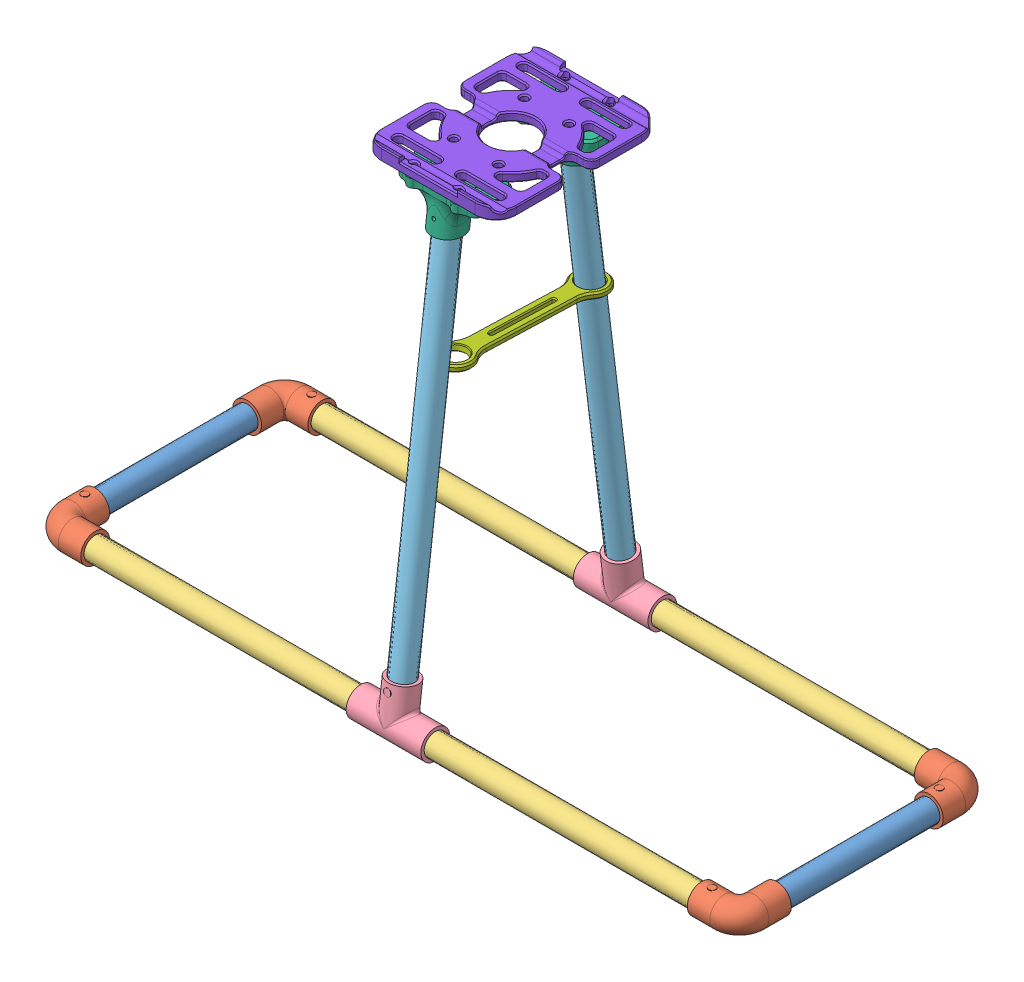
SolidWorks assembly Work Station 010, configuration Predeterminado. Lengths in mm.
Overall size (683 457.41 249.42).
18 component instances, 8 part files, 49 mates.
Components (placement in the parent):
- PVC 90mm-1: PVC 90mm [Predeterminado] at (-25.3323 -2.3435 90) size (21.4 21.4 190)
- PVC 90mm-2: PVC 90mm [Predeterminado] at (629.9177 -2.3435 90) x (-0.183139 -0.983087 0) z (0 0 1) size (21.4 21.4 190)
- PVC 90 Degree Connector-1: PVC 90 Degree Connector [Predeterminado] at (-25.3323 -2.3435 -18.625) x (0 0 -1) z (1 0 0) size (50 27.88 50)
- PVC 90 Degree Connector-2: PVC 90 Degree Connector [Predeterminado] at (629.9177 -2.3435 -18.625) size (50 27.88 50)
- PVC 90 Degree Connector-3: PVC 90 Degree Connector [Predeterminado] at (-25.3323 -2.3435 199.625) x (-1 0 0) z (0 0 -1) size (50 27.88 50)
- PVC 90 Degree Connector-4: PVC 90 Degree Connector [Predeterminado] at (629.9177 -2.3435 199.625) x (0 0 1) z (-1 0 0) size (50 27.88 50)
- PVC 300mm-1: PVC 300mm [Predeterminado] at (138.2927 -2.3435 -18.625) x (0 0.747452 -0.664316) z (1 0 0) size (21.4 21.4 300)
- PVC 300mm-2: PVC 300mm [Predeterminado] at (139.2927 -2.3435 199.625) x (0 0.600314 -0.799764) z (1 0 0) size (21.4 21.4 300)
- PVC 300mm-3: PVC 300mm [Predeterminado] at (465.2927 -2.3435 -18.625) x (0 -0.428598 -0.903495) z (1 0 0) size (21.4 21.4 300)
- PVC 300mm-4: PVC 300mm [Predeterminado] at (465.2927 -2.3435 199.625) x (0 0.714815 0.699313) z (1 0 0) size (21.4 21.4 300)
- PVC T Connector-1: PVC T Connector [Predeterminado] at (301.7927 -2.3435 -18.625) x (0 0.121869 -0.992546) z (1 0 0) size (27.88 50.37 71.8)
- PVC 415mm-1: PVC 415mm [Predeterminado] at (301.7927 217.5055 172.6309) x (-0.698282 -0.087237 -0.710487) z (0 0.992546 -0.121869) size (21.4 21.4 415)
- PVC 415mm-2: PVC 415mm [Predeterminado] at (301.7927 217.7536 8.3995) x (-0.874766 -0.059051 0.480934) z (0 -0.992546 -0.121869) size (21.4 21.4 415)
- PVC T Connector-3: PVC T Connector [Predeterminado] at (301.7927 -2.3435 199.625) x (0 0.121869 0.992546) z (-1 0 0) size (27.88 50.37 71.8)
- Rest Plate Connector 100-1: Rest Plate Connector 100 [Predeterminado] at (301.7927 427.1913 36.6289) size (80 42.81 49)
- Rest Plate Connector 100-2: Rest Plate Connector 100 [Predeterminado] at (301.7927 427.1913 144.3711) x (-1 0 0) z (0 0 -1) size (80 42.81 49)
- Spacer 010-1: Spacer 010 [Predeterminado] at (301.8957 270.2027 80.3275) x (0.001566 0.0349 0.99939) z (-0.999999 -0.000193 0.001573) size (162.46 11.66 32)
- Rest Plate Fixture 010-1: Rest Plate Fixture 010 [Default] at (301.7927 435.6913 90.5) x (0 0 1) z (1 0 0) size (160 12.41 130)
Mates (geometry in assembly coordinates):
- Concéntrica1: concentric aligned: cylinder of PVC 90mm-1 through (-25.3323 -2.3435 185) axis (0 0 -1) radius 10.7; cylinder of PVC 90 Degree Connector-1 through (-25.3323 -2.3435 17.5) axis (0 0 -1) radius 10.7
- Concéntrica2: concentric aligned: cylinder of PVC 90mm-1 through (-25.3323 -2.3435 185) axis (0 0 -1) radius 10.7; cylinder of PVC 90 Degree Connector-3 through (-25.3323 -2.3435 185.125) axis (0 0 -1) radius 10.7
- Concéntrica3: concentric anti-aligned: cylinder of PVC 90mm-2 through (629.9177 -2.3435 185) axis (0 0 -1) radius 10.7; cylinder of PVC 90 Degree Connector-2 through (629.9177 -2.3435 -4.125) axis (0 0 1) radius 10.7
- Concéntrica4: concentric anti-aligned: cylinder of PVC 90mm-2 through (629.9177 -2.3435 185) axis (0 0 -1) radius 10.7; cylinder of PVC 90 Degree Connector-4 through (629.9177 -2.3435 163.5) axis (0 0 1) radius 10.7
- Concéntrica5: concentric aligned: cylinder of PVC 90 Degree Connector-3 through (10.7927 -2.3435 199.625) axis (-1 0 0) radius 10.7; cylinder of PVC 90 Degree Connector-4 through (615.4177 -2.3435 199.625) axis (-1 0 0) radius 10.7
- Concéntrica6: concentric aligned: cylinder of PVC 90 Degree Connector-1 through (-10.8323 -2.3435 -18.625) axis (1 0 0) radius 10.7; cylinder of PVC 90 Degree Connector-2 through (593.7927 -2.3435 -18.625) axis (1 0 0) radius 10.7
- Coincidente1: coincident aligned: plane of PVC 90mm-1 through (-25.3323 -2.3435 -5) normal (0 0 -1); plane of PVC 90mm-2 through (629.9177 -2.3435 -5) normal (0 0 -1)
- Concéntrica7: concentric anti-aligned: cylinder of PVC 90 Degree Connector-1 through (-10.8323 -2.3435 -18.625) axis (1 0 0) radius 10.7; cylinder of PVC 300mm-1 through (288.2927 -2.3435 -18.625) axis (-1 0 0) radius 10.7
- Concéntrica8: concentric aligned: cylinder of PVC 90 Degree Connector-3 through (10.7927 -2.3435 199.625) axis (-1 0 0) radius 10.7; cylinder of PVC 300mm-2 through (289.2927 -2.3435 199.625) axis (-1 0 0) radius 10.7
- Concéntrica9: concentric aligned: cylinder of PVC 90 Degree Connector-4 through (615.4177 -2.3435 199.625) axis (-1 0 0) radius 10.7; cylinder of PVC 300mm-4 through (615.2927 -2.3435 199.625) axis (-1 0 0) radius 10.7
- Concéntrica10: concentric anti-aligned: cylinder of PVC 90 Degree Connector-2 through (593.7927 -2.3435 -18.625) axis (1 0 0) radius 10.7; cylinder of PVC 300mm-3 through (615.2927 -2.3435 -18.625) axis (-1 0 0) radius 10.7
- Concéntrica11: concentric aligned: cylinder of PVC 300mm-3 through (615.2927 -2.3435 -18.625) axis (-1 0 0) radius 10.7; cylinder of PVC T Connector-1 through (337.6927 -2.3435 -18.625) axis (-1 0 0) radius 10.7
- Coincidente2: coincident anti-aligned: plane of PVC 300mm-3 through (315.2927 -2.3435 -18.625) normal (-1 0 0); plane of PVC T Connector-1 through (315.2927 -2.3435 -18.625) normal (1 0 0)
- Coincidente3: coincident anti-aligned: plane of PVC 300mm-1 through (288.2927 -2.3435 -18.625) normal (1 0 0); plane of PVC T Connector-1 through (288.2927 -2.3435 -18.625) normal (-1 0 0)
- Concéntrica12: concentric aligned: cylinder of PVC 300mm-4 through (615.2927 -2.3435 199.625) axis (-1 0 0) radius 10.7; cylinder of PVC T Connector-2 through (338.6927 -2.3435 149.625) axis (-1 0 0) radius 10.7
- Coincidente4: coincident anti-aligned: plane of PVC 300mm-2 through (289.2927 -2.3435 199.625) normal (1 0 0); plane of PVC T Connector-2 through (289.2927 -2.3435 149.625) normal (-1 0 0)
- Coincidente5: coincident anti-aligned: plane of PVC 300mm-4 through (315.2927 -2.3435 199.625) normal (-1 0 0); plane of PVC T Connector-2 through (316.2927 -2.3435 149.625) normal (1 0 0)
- Coincidente6: coincident aligned: plane of PVC 300mm-3 through (615.2927 -2.3435 -18.625) normal (1 0 0); plane of PVC 300mm-4 through (615.2927 -2.3435 199.625) normal (1 0 0)
- Concéntrica13: concentric aligned: cylinder of PVC T Connector-2 through (302.7927 34.1565 149.6639) axis (0 -0.999999 -0.001065) radius 10.7; cylinder of PVC 415mm-1 through (301.7927 423.4588 147.3431) axis (0 -0.992546 0.121869) radius 10.7
- Concéntrica14: concentric anti-aligned: cylinder of PVC T Connector-1 through (301.7927 33.8844 -14.1768) axis (0 -0.992546 -0.121869) radius 10.7; cylinder of PVC 415mm-2 through (301.7927 11.8003 -16.8884) axis (0 0.992546 0.121869) radius 10.7
- Distancia1: distance = 22.25 mm anti-aligned: plane of PVC T Connector-2 through (302.7927 34.1565 149.6639) normal (0 0.999999 0.001065); plane of PVC 415mm-1 through (301.7927 11.5521 197.9188) normal (0 -0.992546 0.121869)
- Distancia2: distance = 22.25 mm anti-aligned: plane of PVC T Connector-1 through (301.7927 33.8844 -14.1768) normal (0 0.992546 0.121869); plane of PVC 415mm-2 through (301.7927 11.8003 -16.8884) normal (0 -0.992546 -0.121869)
- Coincidente9: coincident anti-aligned: plane of PVC 90 Degree Connector-2 through (615.2927 -2.3435 -18.625) normal (-1 0 0); plane of PVC 300mm-3 through (615.2927 -2.3435 -18.625) normal (1 0 0)
- Coincidente10: coincident anti-aligned: plane of PVC 90mm-2 through (629.9177 -2.3435 -5) normal (0 0 -1); plane of PVC 90 Degree Connector-2 through (629.9177 -2.3435 -5) normal (0 0 1)
- Coincidente11: coincident anti-aligned: plane of PVC 90mm-2 through (629.9177 -2.3435 185) normal (0 0 1); plane of PVC 90 Degree Connector-4 through (629.9177 -2.3435 185) normal (0 0 -1)
- Coincidente12: coincident anti-aligned: plane of PVC 90 Degree Connector-3 through (-10.7073 -2.3435 199.625) normal (1 0 0); plane of PVC 300mm-2 through (-10.7073 -2.3435 199.625) normal (-1 0 0)
- Paralelo1: parallel aligned: plane of PVC 90 Degree Connector-3 through (-25.3323 11.6565 173.5157) normal (0 1 0)
- Concéntrica15: concentric anti-aligned: cylinder of PVC 300mm-2 through (289.2927 -2.3435 199.625) axis (-1 0 0) radius 10.7; cylinder of PVC T Connector-3 through (265.8927 -2.3435 199.625) axis (1 0 0) radius 10.7
- Concéntrica16: concentric aligned: cylinder of PVC 415mm-1 through (301.7927 423.4588 147.3431) axis (0 -0.992546 0.121869) radius 10.7; cylinder of PVC T Connector-3 through (301.7927 33.8844 195.1768) axis (0 -0.992546 0.121869) radius 10.7
- Coincidente14: coincident aligned: plane of PVC T Connector-1 through (337.6927 -2.3435 -18.625) normal (1 0 0); plane of PVC T Connector-3 through (337.6927 -2.3435 199.625) normal (1 0 0)
- Distancia3: distance = 22.5 mm anti-aligned: plane of PVC T Connector-3 through (301.7927 33.8844 195.1768) normal (0 0.992546 -0.121869); plane of PVC 415mm-1 through (301.7927 11.5521 197.9188) normal (0 -0.992546 0.121869)
- Coincidente16: coincident anti-aligned: plane of PVC 90 Degree Connector-1 through (-11.7073 -2.3435 -18.625) normal (1 0 0); plane of PVC 300mm-1 through (-11.7073 -2.3435 -18.625) normal (-1 0 0)
- Concéntrica17: concentric anti-aligned: cylinder of PVC 415mm-2 through (301.7927 11.8003 -16.8884) axis (0 0.992546 0.121869) radius 10.7; cylinder of Rest Plate Connector 100-1 through (301.7927 429.9166 34.4499) axis (0 -0.992546 -0.121869) radius 11.175
- Coincidente17: coincident anti-aligned: plane of Rest Plate 010-1 through (301.7918 423.7054 56.3705) normal (0 -1 0); plane of Rest Plate Connector 100-1 through (301.7927 427.1913 36.6289) normal (0 1 0)
- Concéntrica18: concentric aligned: cylinder of Rest Plate 010-1 through (323.2777 423.7054 32.3705) axis (0 1 0) radius 1.7; cylinder of Rest Plate Connector 100-1 through (323.2777 386.2677 17.6189) axis (0 1 0) radius 1.5
- Paralelo2: parallel aligned: cylinder of Rest Plate 010-1 through (280.306 423.7054 71.3705) axis (0 1 0) radius 1.7; cylinder of Rest Plate Connector 100-1 through (280.3077 386.2677 56.6189) axis (0 1 0) radius 1.5
- Concéntrica20: concentric aligned: cylinder of PVC 415mm-1 through (301.7927 423.4588 147.3431) axis (0 -0.992546 0.121869) radius 10.7; cylinder of Rest Plate Connector 100-2 through (301.7927 429.9166 146.5501) axis (0 -0.992546 0.121869) radius 11.175
- Coincidente18: coincident anti-aligned: plane of Rest Plate Connector 100-2 through (301.7927 427.1913 144.3711) normal (0 1 0); plane of Rest Plate 010-2 through (301.7935 423.7054 124.6295) normal (0 -1 0)
- Coincidente21: coincident aligned: plane of Rest Plate 010-1 through (301.7918 438.7054 56.3705) normal (0 1 0); plane of Rest Plate 010-2 through (301.7935 438.7054 124.6295) normal (0 1 0)
- Concéntrica28: concentric aligned: cylinder of Rest Plate Connector 100-2 through (280.3077 386.2677 163.3811) axis (0 1 0) radius 1.5; cylinder of Rest Plate 010-2 through (280.3077 423.7054 148.6295) axis (0 1 0) radius 1.7
- Concéntrica29: concentric aligned: cylinder of Rest Plate Connector 100-2 through (280.3077 386.2677 124.3811) axis (0 1 0) radius 1.5; cylinder of Rest Plate 010-2 through (280.3077 423.7054 109.6295) axis (0 1 0) radius 1.7
- Concéntrica30: concentric aligned: cylinder of PVC 415mm-2 through (301.7927 11.8003 -16.8884) axis (0 0.992546 0.121869) radius 10.7; cylinder of Spacer 010-1 through (301.7927 265.512 14.2635) axis (0 0.992546 0.121869) radius 10.925
- Width1: width anti-aligned: plane of Rest Plate 010-1 through (216.7918 438.7054 31.3705) normal (-1 0 0); plane of Rest Plate Fixture 010-1 through (386.7918 438.7054 31.3705) normal (1 0 0); plane of Rest Plate 010-1 through (366.7927 427.1913 10.5) normal (1 0 0); plane of Rest Plate Fixture 010-1 through (236.7927 427.1913 10.5) normal (-1 0 0)
- Width2: width aligned: plane of Rest Plate 010-1 through (216.7918 438.7054 31.3705) normal (0 0 -1); plane of Rest Plate Fixture 010-1 through (386.7935 438.7054 149.6295) normal (0 0 1); plane of Rest Plate 010-2 through (232.0911 435.0115 29.6831) normal (0 0 -1); plane of Rest Plate Fixture 010-1 through (232.0911 435.0115 147.9422) normal (0 0 1)
- Coincident1: coincident aligned: plane of Rest Plate Connector 100-1 through (301.7927 427.1913 36.6289) normal (0 1 0); plane of Rest Plate Connector 100-2 through (301.7927 427.1913 144.3711) normal (0 1 0)
- Parallel1: parallel aligned: plane of Rest Plate Connector 100-1 through (301.7927 427.1913 36.6289) normal (0 1 0)
- Width3: width anti-aligned: plane of Rest Plate Fixture 010-1 through (236.7927 427.1913 170.5) normal (0 0 1); plane of Rest Plate Fixture 010-1 through (236.7927 427.1913 10.5) normal (0 0 -1); plane of Rest Plate Connector 100-1 through (261.7927 417.1913 16.6289) normal (0 0 -1); plane of Rest Plate Connector 100-2 through (341.7927 417.1913 164.3711) normal (0 0 1)
- Width4: width anti-aligned: plane of Rest Plate Fixture 010-1 through (236.7927 427.1913 10.5) normal (-1 0 0); plane of Rest Plate Fixture 010-1 through (366.7927 427.1913 10.5) normal (1 0 0); plane of Rest Plate Connector 100-2 through (341.7927 417.1913 164.3711) normal (1 0 0); plane of Rest Plate Connector 100-2 through (261.7927 417.1913 164.3711) normal (-1 0 0)
- Coincident3: coincident anti-aligned: plane of Rest Plate Connector 100-2 through (301.7927 427.1913 144.3711) normal (0 1 0); plane of Rest Plate Fixture 010-1 through (301.7927 427.1913 90.5) normal (0 -1 0)
